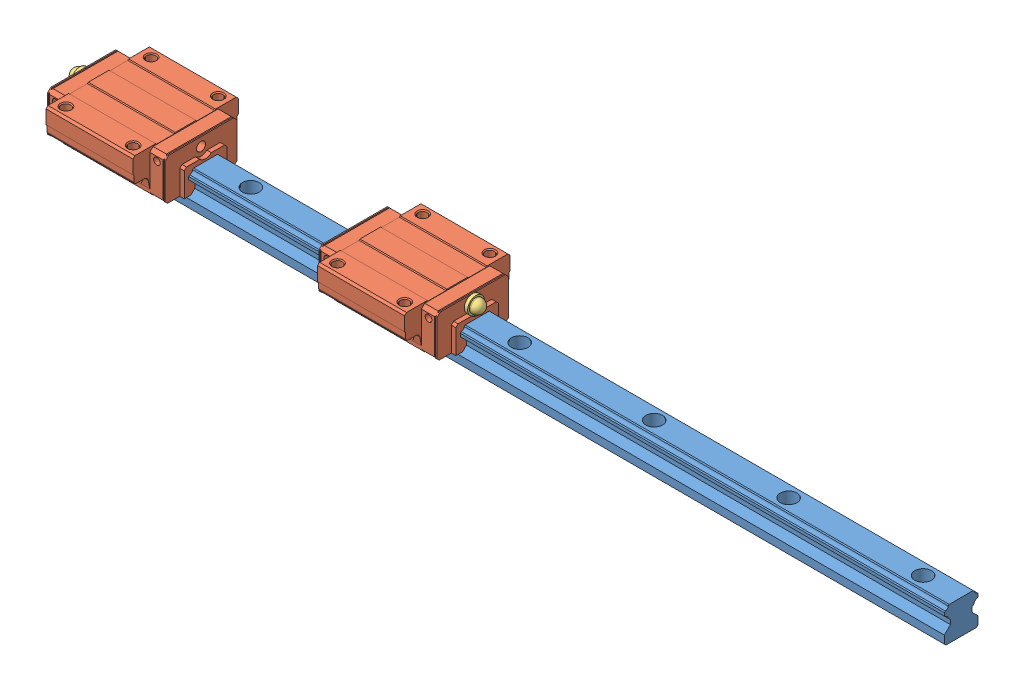
SolidWorks assembly Rail HSR15A_394mm, configuration По умолчанию. Lengths in mm.
Overall size (396.8 24 47).
5 component instances, 3 part files, 10 mates.
Components (placement in the parent):
- Rail HSR15A_394mm-1: Rail HSR15A_394mm [По умолчанию] at origin size (394 15 15)
- HSR15AUU-1: HSR15AUU [По умолчанию] at (132.7 4.7 0) size (56.6 19.3 47)
- HSR15AUU-2: HSR15AUU [По умолчанию] at (11.5 4.7 0) size (56.6 19.3 47)
- PB1021B_grease_nipple-1: PB1021B_grease_nipple [По умолчанию] at (-14.8 19.7 0) size (9.5 7.5 7.5)
- PB1021B_grease_nipple-2: PB1021B_grease_nipple [По умолчанию] at (159 19.7 0) x (-1 0 0) z (0 0 1) size (9.5 7.5 7.5)
Mates (geometry in assembly coordinates):
- Concentric1: concentric aligned: cylinder of Rail HSR15A_394mm-1 through (377 14.813 -7.3005) axis (-1 0 0) radius 1.56; cylinder of HSR15AUU-1 through (161 14.813 -7.3005) axis (-1 0 0) radius 1.56
- Concentric2: concentric aligned: cylinder of Rail HSR15A_394mm-1 through (377 14.813 7.3005) axis (-1 0 0) radius 1.56; cylinder of HSR15AUU-1 through (161 14.813 7.3005) axis (-1 0 0) radius 1.56
- Concentric3: concentric aligned: cylinder of Rail HSR15A_394mm-1 through (377 14.813 -7.3005) axis (-1 0 0) radius 1.56; cylinder of HSR15AUU-2 through (39.8 14.813 -7.3005) axis (-1 0 0) radius 1.56
- Concentric4: concentric aligned: cylinder of Rail HSR15A_394mm-1 through (377 14.813 7.3005) axis (-1 0 0) radius 1.56; cylinder of HSR15AUU-2 through (39.8 14.813 7.3005) axis (-1 0 0) radius 1.56
- Distance1: distance = 160 mm anti-aligned: plane of HSR15AUU-1 through (152.1 14 22) normal (1 0 0); plane of HSR15AUU-2 through (-7.9 14 22) normal (-1 0 0)
- Concentric5: concentric aligned: cylinder of HSR15AUU-2 through (-10.3 19.7 0) axis (1 0 0) radius 2; cylinder of PB1021B_grease_nipple-1 through (-10.3 19.7 0) axis (1 0 0) radius 2
- Coincident1: coincident anti-aligned: plane of HSR15AUU-2 through (-14.8 4.7 0) normal (-1 0 0); plane of PB1021B_grease_nipple-1 through (-14.8 23.45 0) normal (1 0 0)
- Concentric6: concentric anti-aligned: cylinder of HSR15AUU-1 through (161 19.7 0) axis (1 0 0) radius 2; cylinder of PB1021B_grease_nipple-2 through (154.5 19.7 0) axis (-1 0 0) radius 2
- Coincident2: coincident anti-aligned: plane of HSR15AUU-1 through (159 4.7 0) normal (1 0 0); plane of PB1021B_grease_nipple-2 through (159 15.95 0) normal (-1 0 0)
- Distance2: limit distance = 216 mm aligned: plane of HSR15AUU-1 through (161 4.7 0) normal (1 0 0); plane of Rail HSR15A_394mm-1 through (377 9.588 7.3005) normal (1 0 0)
